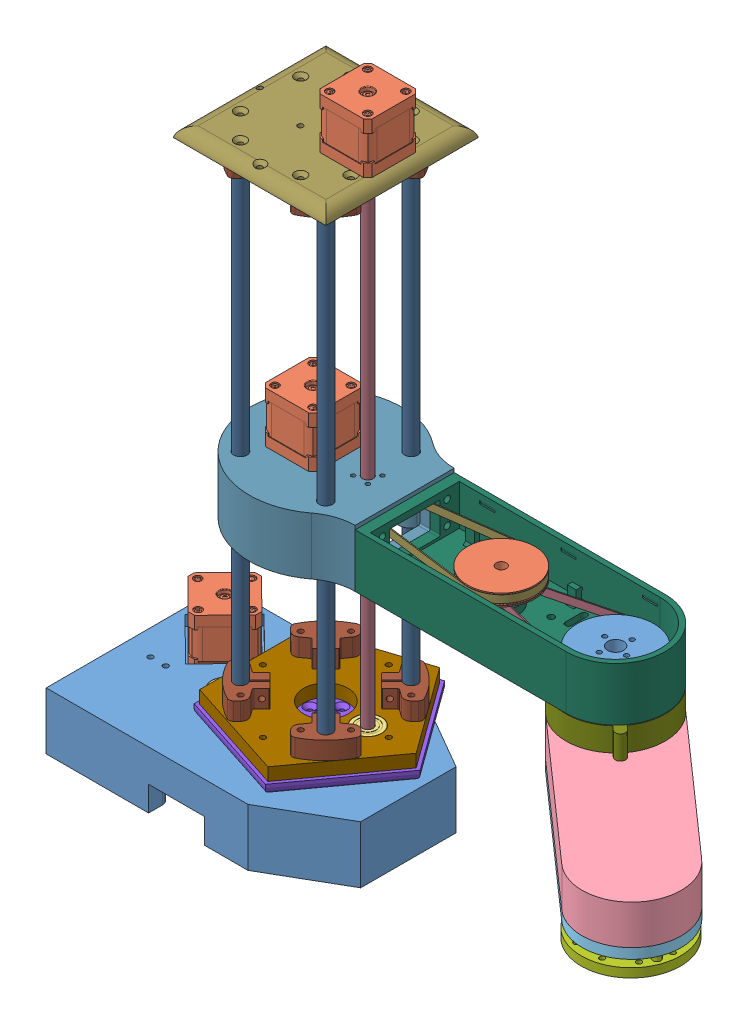
SolidWorks assembly SCARA ENSAMBLE, configuration SCARA Robot. Lengths in mm.
Overall size (541.01 508 220.87).
62 component instances, 33 part files, 149 mates.
Components (placement in the parent):
- 0-Base-1: 0-Base [Base] at origin size (215 45 140)
- Stepper NEMA 17 -  20mm shaft-1: Stepper NEMA 17 -  20mm shaft [Stepper NEMA 17 -  20mm shaft] at (-89.369 63.0261 0.1561) x (-0.712104 0 -0.702074) z (0 -1 0) size (41 41 60)
- Ball Bearing 608 - 8x22x7mm-2: Ball Bearing 608 - 8x22x7mm [Ball Bearing 608 - 8x22x7mm] at (-36.5 3 0) x (0.982643 0 -0.185507) z (0.185507 0 0.982643) size (22 7 22)
- Ball Bearing 608 - 8x22x7mm-3: Ball Bearing 608 - 8x22x7mm [Ball Bearing 608 - 8x22x7mm] at (-36.5 -7.5 0) x (0.997797 0 -0.066338) z (0.066338 0 0.997797) size (22 7 22)
- Thrust Bearing - 40x60x13-3: Thrust Bearing - 40x60x13 [Thrust Bearing - 40x60x13] at (42.5 -13 0) size (60 13 60)
- Thrust Bearing - 40x60x13-4: Thrust Bearing - 40x60x13 [Thrust Bearing - 40x60x13] at (42.5 10 0) x (0.998314 0 0.058039) z (-0.058039 0 0.998314) size (60 13 60)
- 02-ENGRANEGT2J1BASE110-2: 02-ENGRANEGT2J1BASE110 [GT2 Pulley - Parametric] at (42.5 -11.2 0) x (-1 0 0) z (0 0 1) size (71.92 22.4 71.92)
- 01-ENGRANEGT2J122-80-2: 01-ENGRANEGT2J122-80 [GT2 Pulley - Parametric] at (-36.5 -26.3 0) x (0.998061 0 0.062248) z (-0.062248 0 0.998061) size (52.82 18.8 52.82)
- GT2 Pulley - Parametric-1: GT2 Pulley - Parametric [GT2 Pulley - Parametric] at (-69.2568 -19.3 -32.2954) x (-0.837169 0 -0.546944) z (-0.546944 0 0.837169) size (14.62 15.2 14.62)
- 1-J1 ACOPLEMOD-1: 1-J1 ACOPLEMOD [J1 coupler] at (42.5 23 0) x (0 0 1) z (-1 0 0) size (141.07 27 134.16)
- 2-TapaZ-2: 2-TapaZ [Z-axis Bottom Plate] at (42.5 31 0) x (0 0 -1) z (1 0 0) size (135.19 10 128.57)
- Smooth Rod D10mm L400mm-1: Smooth Rod D10mm L400mm [Smooth Rod D10mm L400mm] at (76.0876 25 -33.5876) x (-0.2209 0 0.975296) z (-0.975296 0 -0.2209) size (10 400 10)
- Smooth Rod D10mm L400mm-2: Smooth Rod D10mm L400mm [Smooth Rod D10mm L400mm] at (76.0876 25 33.5876) size (10 400 10)
- Smooth Rod D10mm L400mm-3: Smooth Rod D10mm L400mm [Smooth Rod D10mm L400mm] at (8.9124 25 33.5876) size (10 400 10)
- Smooth Rod D10mm L400mm-4: Smooth Rod D10mm L400mm [Smooth Rod D10mm L400mm] at (8.9124 25 -33.5876) size (10 400 10)
- 11-SOPORTEVARILLA-1: 11-SOPORTEVARILLA [Smooth Rod Clamp] at (76.0876 41 33.5876) x (0.707107 0 -0.707107) z (0.707107 0 0.707107) size (39.1 14 26.4)
- 11-SOPORTEVARILLA-2: 11-SOPORTEVARILLA [Smooth Rod Clamp] at (8.9124 41 33.5876) x (0.707107 0 0.707107) z (-0.707107 0 0.707107) size (39.1 14 26.4)
- 11-SOPORTEVARILLA-3: 11-SOPORTEVARILLA [Smooth Rod Clamp] at (8.9124 41 -33.5876) x (-0.707107 0 0.707107) z (-0.707107 0 -0.707107) size (39.1 14 26.4)
- 11-SOPORTEVARILLA-4: 11-SOPORTEVARILLA [Smooth Rod Clamp] at (76.0876 41 -33.5876) x (-0.707107 0 -0.707107) z (0.707107 0 -0.707107) size (39.1 14 26.4)
- 10-TOPZ-1: 10-TOPZ [Z-axis Top Plate] at (42.5 425 0) x (0 0 -1) z (1 0 0) size (120 26 120)
- 11-SOPORTEVARILLA-5: 11-SOPORTEVARILLA [Smooth Rod Clamp] at (8.9124 411 33.5876) x (0.707107 0 0.707107) z (-0.707107 0 0.707107) size (39.1 14 26.4)
- 11-SOPORTEVARILLA-6: 11-SOPORTEVARILLA [Smooth Rod Clamp] at (76.0876 411 33.5876) x (0.707107 0 -0.707107) z (0.707107 0 0.707107) size (39.1 14 26.4)
- 11-SOPORTEVARILLA-7: 11-SOPORTEVARILLA [Smooth Rod Clamp] at (76.0876 411 -33.5876) x (-0.707107 0 -0.707107) z (0.707107 0 -0.707107) size (39.1 14 26.4)
- 11-SOPORTEVARILLA-8: 11-SOPORTEVARILLA [Smooth Rod Clamp] at (8.9124 411 -33.5876) x (-0.707107 0 0.707107) z (-0.707107 0 -0.707107) size (39.1 14 26.4)
- Lead Screw D8mm L380mm-1: Lead Screw D8mm L380mm [Lead Screw D8mm L380mm] at (75.5 33 0) x (0.999653 0 0.026358) z (-0.026358 0 0.999653) size (8 380 8)
- Ball Bearing 608 - 8x22x7mm-4: Ball Bearing 608 - 8x22x7mm [Ball Bearing 608 - 8x22x7mm] at (75.5 34 0) x (0.948058 0 -0.318097) z (0.318097 0 0.948058) size (22 7 22)
- Stepper NEMA 17 -  20mm shaft-2: Stepper NEMA 17 -  20mm shaft [Stepper NEMA 17 -  20mm shaft] at (38.2709 494.0261 8.4614) x (0 0 -1) z (0 -1 0) size (41 41 60)
- 3-J1CENTRAL-1: 3-J1CENTRAL [Z-axis Mount Platform] at (42.5 211.1984 0) x (0 0 1) z (1 0 0) size (120 45 122)
- 4-J1CENTRALBRAZO-1: 4-J1CENTRALBRAZO [Arm 1] at (270.5 166.1984 0) size (205 42 78)
- Ball Bearing 608 - 8x22x7mm-5: Ball Bearing 608 - 8x22x7mm [Ball Bearing 608 - 8x22x7mm] at (180.5 182.1984 0) x (0.62791 0 0.778286) z (0.778286 0 -0.62791) size (22 7 22)
- Ball Bearing 608 - 8x22x7mm-6: Ball Bearing 608 - 8x22x7mm [Ball Bearing 608 - 8x22x7mm] at (180.5 173.1984 0) x (0.619443 0 0.785042) z (0.785042 0 -0.619443) size (22 7 22)
- 5-COPLEJ1J2-1: 5-COPLEJ1J2 [J2 Coupler] at (270.5 147.1984 0) x (0.198234 0 -0.980155) z (0.980155 0 0.198234) size (78 24 80.24)
- Thrust Bearing 35x52x12mm-1: Thrust Bearing 35x52x12mm [Thrust Bearing 35x52x12mm] at (270.5 154.1984 0) x (1 0 0.000333) z (-0.000333 0 1) size (52 12 52)
- Ball Bearing 30x42x7mm-1: Ball Bearing 30x42x7mm [Ball Bearing 30x42x7mm] at (270.5 169.1984 0) x (1 0 0.000333) z (-0.000333 0 1) size (42 7 42)
- GT2 Pulley - 92 teeth - J2-1: GT2 Pulley - 92 teeth - J2 [GT2 Pulley - Parametric] at (270.5 184.3984 0) x (0.980155 0 0.198234) z (-0.198234 0 0.980155) size (60.46 20.4 60.46)
- GT2 Pulley - 23 - 80 teeth-1: GT2 Pulley - 23 - 80 teeth [GT2 Pulley - Parametric] at (180.5 200.9984 0) x (-0.873164 0 -0.487427) z (-0.487427 0 0.873164) size (52.82 18.8 52.82)
- Thrust Bearing 35x52x12mm-2: Thrust Bearing 35x52x12mm [Thrust Bearing 35x52x12mm] at (270.5 176.1984 0) x (1 0 0.000333) z (-0.000333 0 1) size (52 12 52)
- Stepper NEMA 17 -  20mm shaft-3: Stepper NEMA 17 -  20mm shaft [Stepper NEMA 17 -  20mm shaft] at (-4.7291 272.2245 8.4614) x (0 0 -1) z (0 -1 0) size (41 41 60)
- GT2 Pulley - Parametric-2: GT2 Pulley - Parametric [GT2 Pulley - Parametric] at (32.5 200.9984 0) x (-0.529245 0 -0.848469) z (-0.848469 0 0.529245) size (14.62 15.2 14.62)
- Linear Bearing 10x19x29mm-1: Linear Bearing 10x19x29mm [Linear Bearing 10x19x29mm] at (8.9124 176.1984 -33.5876) x (0.996362 0 -0.085221) z (0.085221 0 0.996362) size (19 29 19)
- Linear Bearing 10x19x29mm-2: Linear Bearing 10x19x29mm [Linear Bearing 10x19x29mm] at (76.0876 176.1984 -33.5876) x (0.940518 0 0.339744) z (-0.339744 0 0.940518) size (19 29 19)
- Linear Bearing 10x19x29mm-3: Linear Bearing 10x19x29mm [Linear Bearing 10x19x29mm] at (8.9124 176.1984 33.5876) size (19 29 19)
- Linear Bearing 10x19x29mm-6: Linear Bearing 10x19x29mm [Linear Bearing 10x19x29mm] at (76.0876 176.1984 33.5876) size (19 29 19)
- 6-J2BRZO-1: 6-J2BRZO [Arm 2] at (378.46 147.1984 95.2924) x (0.749722 0 0.661753) z (0.661753 0 -0.749722) size (222 31 78)
- 7-J2TAPABRZO-1: 7-J2TAPABRZO [Arm 2 Cover] at (378.46 108.1984 95.2924) x (0.749722 0 0.661753) z (-0.661753 0 0.749722) size (222 8 78)
- Micro switch-1: Micro switch [Micro switch] at (217.6469 166.1984 9.5547) x (0.882948 0 -0.469472) z (0 -1 0) size (21.91 25.05 6)
- 8-J3COPLE-1: 8-J3COPLE [J3 Coupler] at (372.8371 90.1984 90.3293) x (-0.943757 0 -0.330639) z (0.330639 0 -0.943757) size (77.59 22 78)
- Ball Bearing 30x42x7mm-2: Ball Bearing 30x42x7mm [Ball Bearing 30x42x7mm] at (372.8371 116.1984 90.3293) x (-0.837351 0 -0.546665) z (-0.546665 0 0.837351) size (42 7 42)
- Thrust Bearing 35x52x12mm-3: Thrust Bearing 35x52x12mm [Thrust Bearing 35x52x12mm] at (372.8371 116.1984 90.3293) x (0.88853 0 -0.458819) z (0.458819 0 0.88853) size (52 12 52)
- Thrust Bearing 35x52x12mm-4: Thrust Bearing 35x52x12mm [Thrust Bearing 35x52x12mm] at (372.8371 108.1984 90.3293) x (-0.531744 0 -0.846905) z (-0.846905 0 0.531744) size (52 12 52)
- GT2 Pulley - 90 teeth - J3-1: GT2 Pulley - 90 teeth - J3 [GT2 Pulley - Parametric] at (372.8371 126.3984 90.3293) x (-0.330639 0 0.943757) z (-0.943757 0 -0.330639) size (59.19 21.4 59.19)
- GT2 Pulley - Parametric-3: GT2 Pulley - Parametric [GT2 Pulley - Parametric] at (266.0017 126.3984 -3.9705) x (0.907133 0 -0.420845) z (0.420845 0 0.907133) size (14.62 15.2 14.62)
- Micro switch-3: Micro switch [Micro switch] at (-8.7411 16 2.5547) x (0.882948 0 -0.469472) z (0 -1 0) size (21.91 25.05 6)
- Micro switch-4: Micro switch [Micro switch] at (333.7206 108.1984 68.5469) x (0.972639 0 0.23232) z (0 -1 0) size (21.91 25.05 6)
- Lead Screw Nut 8mm-1: Lead Screw Nut 8mm [Lead Screw Nut 8mm] at (75.5 201.6984 0) size (22 15 22)
- Micro switch-5: Micro switch [Micro switch] at (14.25 412 6) x (1 0 0) z (0 0 -1) size (21.91 25.05 6)
- GT2 Belt 200mm-1: GT2 Belt 200mm [GT2 Belt 400mm] at (-36.5 -25.3 0) x (0.712104 0 0.702074) z (-0.702074 0 0.712104) size (79.45 6 52.6)
- GT2 Belt 300mm 2-1: GT2 Belt 300mm 2 [GT2 Belt 400mm] at (42.5 -17.2 0) size (122.6 6 71.6)
- GT2 Belt 400mm-1: GT2 Belt 400mm [GT2 Belt 400mm] at (180.5 194.9984 0) size (181.45 6 52.6)
- GT2 Belt 300mm-1: GT2 Belt 300mm [GT2 Belt 400mm] at (270.5 185.3984 0) size (128.2 6 60.2)
- GT2 Belt 400mm 2-1: GT2 Belt 400mm 2 [GT2 Belt 400mm] at (372.8371 126.3984 90.3293) x (0.749722 0 0.661753) z (-0.661753 0 0.749722) size (179.1 6 58.9)
- Ball Bearing 35x47x7mm-1: Ball Bearing 35x47x7mm [Ball Bearing 30x42x7mm] at (42.5 0 0) x (0.999968 0 0.008039) z (-0.008039 0 0.999968) size (47 7 47)
Mates (geometry in assembly coordinates):
- Concentric1: concentric aligned: cylinder of Base-1 through (-69.2568 0 -32.2954) axis (0 1 0) radius 12.5; cylinder of Stepper NEMA 17 -  20mm shaft-1 through (-69.2568 0.01 -32.2954) axis (0 1 0) radius 11.5
- Parallel1: parallel anti-aligned: plane of Base-1 through (-69.0361 2 -1.1835) normal (0.702074 0 -0.712104); plane of Stepper NEMA 17 -  20mm shaft-1 through (-71.5435 2 -5.762) normal (-0.702074 0 0.712104)
- Coincident2: coincident anti-aligned: plane of Base-1 through (0 2 0) normal (0 1 0); plane of Stepper NEMA 17 -  20mm shaft-1 through (-83.6493 2 -17.6973) normal (0 -1 0)
- Concentric2: concentric anti-aligned: cylinder of Base-1 through (-36.5 3 0) axis (0 1 0) radius 11; cylinder of Ball Bearing 608 - 8x22x7mm-2 through (-36.5 10 0) axis (0 -1 0) radius 11
- Coincident3: coincident anti-aligned: plane of Base-1 through (-36.5 3 0) normal (0 1 0); plane of Ball Bearing 608 - 8x22x7mm-2 through (-36.5 3 0) normal (0 -1 0)
- Concentric3: concentric anti-aligned: cylinder of Base-1 through (-36.5 -8.5 0) axis (0 1 0) radius 11; cylinder of Ball Bearing 608 - 8x22x7mm-3 through (-36.5 -0.5 0) axis (0 -1 0) radius 11
- Concentric4: concentric aligned: cylinder of Base-1 through (42.5 0 0) axis (0 1 0) radius 20; cylinder of Thrust Bearing - 40x60x13-4 through (42.5 19.2 0) axis (0 1 0) radius 30
- Coincident5: coincident anti-aligned: plane of Base-1 through (0 10 0) normal (0 1 0); plane of Thrust Bearing - 40x60x13-4 through (42.5 10 0) normal (0 -1 0)
- Concentric5: concentric anti-aligned: cylinder of Base-1 through (42.5 -8 0) axis (0 1 0) radius 30.5; cylinder of Thrust Bearing - 40x60x13-3 through (42.5 -9.2 0) axis (0 -1 0) radius 30
- Coincident6: coincident anti-aligned: plane of Base-1 through (0 0 0) normal (0 -1 0); plane of Thrust Bearing - 40x60x13-3 through (42.5 0 0) normal (0 1 0)
- Concentric6: concentric anti-aligned: cylinder of Ball Bearing 608 - 8x22x7mm-3 through (-36.5 -0.5 0) axis (0 -1 0) radius 4; cylinder of GT2 Pulley - 22 - 80 teeth-2 through (-36.5 -27.5 0) axis (0 1 0) radius 4
- Concentric8: concentric anti-aligned: cylinder of Thrust Bearing - 40x60x13-3 through (42.5 -3.8 0) axis (0 1 0) radius 20; cylinder of GT2 Pulley - 110 teeth - J1-2 through (42.5 3 0) axis (0 -1 0) radius 17.5
- Coincident9: coincident anti-aligned: plane of Thrust Bearing - 40x60x13-3 through (42.5 -13 0) normal (0 -1 0); plane of GT2 Pulley - 110 teeth - J1-2 through (42.5 -13 0) normal (0 1 0)
- Concentric9: concentric anti-aligned: cylinder of Stepper NEMA 17 -  20mm shaft-1 through (-69.2568 -20 -32.2954) axis (0 1 0) radius 2.5; cylinder of GT2 Pulley - Parametric-1 through (-69.2568 -12.3 -32.2954) axis (0 -1 0) radius 3
- Coincident10: coincident aligned: plane of GT2 Pulley - 22 - 80 teeth-2 through (-36.5 -19.3 0) normal (0 -1 0); plane of GT2 Pulley - Parametric-1 through (-69.2568 -19.3 -32.2954) normal (0 -1 0)
- Coincident11: coincident anti-aligned: plane of Thrust Bearing - 40x60x13-4 through (42.5 23 0) normal (0 1 0); plane of J1 coupler-1 through (42.5 23 0) normal (0 -1 0)
- Concentric10: concentric: cylinder of Thrust Bearing - 40x60x13-4 through (42.5 18.2 0) axis (0 -1 0) radius 30; cylinder of J1 coupler-1 through (42.5 31 0) axis (0 -1 0) radius 60
- Concentric11: concentric anti-aligned: cylinder of GT2 Pulley - 110 teeth - J1-2 through (55 3 0) axis (0 -1 0) radius 1.8; cylinder of J1 coupler-1 through (55 31 0) axis (0 1 0) radius 1.8
- Coincident13: coincident anti-aligned: plane of Base-1 through (-36.5 -0.5 0) normal (0 -1 0); plane of Ball Bearing 608 - 8x22x7mm-3 through (-36.5 -0.5 0) normal (0 1 0)
- Concentric12: concentric anti-aligned: cylinder of J1 coupler-1 through (76.0876 23 -33.5876) axis (0 1 0) radius 3.875; cylinder of Smooth Rod D10mm L400mm-1 through (76.0876 425 -33.5876) axis (0 -1 0) radius 5
- Coincident14: coincident: plane of J1 coupler-1 through (76.0876 25 -33.5876) normal (0 1 0); plane of Smooth Rod D10mm L400mm-1 through (76.0876 25 -33.5876) normal (0 -1 0)
- Concentric13: concentric anti-aligned: cylinder of J1 coupler-1 through (8.9124 23 -33.5876) axis (0 1 0) radius 3.875; cylinder of Smooth Rod D10mm L400mm-4 through (8.9124 425 -33.5876) axis (0 -1 0) radius 5
- Concentric14: concentric anti-aligned: cylinder of J1 coupler-1 through (8.9124 23 33.5876) axis (0 1 0) radius 3.875; cylinder of Smooth Rod D10mm L400mm-3 through (8.9124 425 33.5876) axis (0 -1 0) radius 5
- Concentric15: concentric anti-aligned: cylinder of J1 coupler-1 through (76.0876 23 33.5876) axis (0 1 0) radius 3.875; cylinder of Smooth Rod D10mm L400mm-2 through (76.0876 425 33.5876) axis (0 -1 0) radius 5
- Coincident15: coincident aligned: plane of Smooth Rod D10mm L400mm-1 through (76.0876 425 -33.5876) normal (0 1 0); plane of Smooth Rod D10mm L400mm-2 through (76.0876 425 33.5876) normal (0 1 0)
- Coincident16: coincident aligned: plane of Smooth Rod D10mm L400mm-1 through (76.0876 425 -33.5876) normal (0 1 0); plane of Smooth Rod D10mm L400mm-3 through (8.9124 425 33.5876) normal (0 1 0)
- Coincident17: coincident aligned: plane of Smooth Rod D10mm L400mm-1 through (76.0876 425 -33.5876) normal (0 1 0); plane of Smooth Rod D10mm L400mm-4 through (8.9124 425 -33.5876) normal (0 1 0)
- Concentric16: concentric: cylinder of J1 coupler-1 through (42.5 31 0) axis (0 -1 0) radius 60; cylinder of Z-axis Bottom Plate-2 through (42.5 41 0) axis (0 -1 0) radius 60
- Concentric17: concentric anti-aligned: cylinder of Z-axis Bottom Plate-2 through (76.0876 31 -33.5876) axis (0 1 0) radius 4.975; cylinder of Smooth Rod D10mm L400mm-1 through (76.0876 425 -33.5876) axis (0 -1 0) radius 5
- Coincident18: coincident anti-aligned: plane of J1 coupler-1 through (42.5 31 0) normal (0 1 0); plane of Z-axis Bottom Plate-2 through (42.5 31 0) normal (0 -1 0)
- Concentric18: concentric aligned: cylinder of Smooth Rod D10mm L400mm-2 through (76.0876 425 33.5876) axis (0 -1 0) radius 5; cylinder of Smooth Rod Clamp-1 through (76.0876 55 33.5876) axis (0 -1 0) radius 4
- Concentric19: concentric anti-aligned: cylinder of Z-axis Bottom Plate-2 through (66.1881 31 43.4871) axis (0 1 0) radius 2.05; cylinder of Smooth Rod Clamp-1 through (66.1881 55 43.4871) axis (0 -1 0) radius 2.05
- Coincident19: coincident anti-aligned: plane of Z-axis Bottom Plate-2 through (42.5 41 0) normal (0 1 0); plane of Smooth Rod Clamp-1 through (66.1881 41 43.4871) normal (0 -1 0)
- Coincident20: coincident anti-aligned: plane of Z-axis Bottom Plate-2 through (42.5 41 0) normal (0 1 0); plane of Smooth Rod Clamp-4 through (85.9871 41 -23.6881) normal (0 -1 0)
- Concentric20: concentric aligned: cylinder of Smooth Rod D10mm L400mm-1 through (76.0876 425 -33.5876) axis (0 -1 0) radius 5; cylinder of Smooth Rod Clamp-4 through (76.0876 55 -33.5876) axis (0 -1 0) radius 4
- Concentric21: concentric anti-aligned: cylinder of Z-axis Bottom Plate-2 through (66.1881 31 -43.4871) axis (0 1 0) radius 2.05; cylinder of Smooth Rod Clamp-4 through (66.1881 55 -43.4871) axis (0 -1 0) radius 2.05
- Coincident21: coincident anti-aligned: plane of Z-axis Bottom Plate-2 through (42.5 41 0) normal (0 1 0); plane of Smooth Rod Clamp-2 through (-0.9871 41 23.6881) normal (0 -1 0)
- Concentric22: concentric aligned: cylinder of Smooth Rod D10mm L400mm-3 through (8.9124 425 33.5876) axis (0 -1 0) radius 5; cylinder of Smooth Rod Clamp-2 through (8.9124 55 33.5876) axis (0 -1 0) radius 4
- Concentric23: concentric anti-aligned: cylinder of Z-axis Bottom Plate-2 through (18.8119 31 43.4871) axis (0 1 0) radius 2.05; cylinder of Smooth Rod Clamp-2 through (18.8119 55 43.4871) axis (0 -1 0) radius 2.05
- Concentric24: concentric aligned: cylinder of Smooth Rod D10mm L400mm-4 through (8.9124 425 -33.5876) axis (0 -1 0) radius 5; cylinder of Smooth Rod Clamp-3 through (8.9124 55 -33.5876) axis (0 -1 0) radius 4
- Concentric25: concentric anti-aligned: cylinder of Z-axis Bottom Plate-2 through (-0.9871 31 -23.6881) axis (0 1 0) radius 2.05; cylinder of Smooth Rod Clamp-3 through (-0.9871 55 -23.6881) axis (0 -1 0) radius 2.05
- Coincident22: coincident anti-aligned: plane of Z-axis Bottom Plate-2 through (42.5 41 0) normal (0 1 0); plane of Smooth Rod Clamp-3 through (18.8119 41 -43.4871) normal (0 -1 0)
- Coincident23: coincident anti-aligned: plane of Z-axis Top Plate-1 through (42.5 425 0) normal (0 -1 0); plane of Smooth Rod Clamp-6 through (66.1881 425 43.4871) normal (0 1 0)
- Concentric26: concentric anti-aligned: cylinder of Z-axis Top Plate-1 through (85.9871 425 23.6881) axis (0 1 0) radius 2.05; cylinder of Smooth Rod Clamp-6 through (85.9871 425 23.6881) axis (0 -1 0) radius 2.05
- Concentric27: concentric anti-aligned: cylinder of Z-axis Top Plate-1 through (66.1881 425 43.4871) axis (0 1 0) radius 2.05; cylinder of Smooth Rod Clamp-6 through (66.1881 425 43.4871) axis (0 -1 0) radius 2.05
- Coincident24: coincident anti-aligned: plane of Z-axis Top Plate-1 through (42.5 425 0) normal (0 -1 0); plane of Smooth Rod Clamp-8 through (18.8119 425 -43.4871) normal (0 1 0)
- Concentric28: concentric anti-aligned: cylinder of Z-axis Top Plate-1 through (18.8119 425 -43.4871) axis (0 1 0) radius 2.05; cylinder of Smooth Rod Clamp-8 through (18.8119 425 -43.4871) axis (0 -1 0) radius 2.05
- Concentric29: concentric anti-aligned: cylinder of Z-axis Top Plate-1 through (-0.9871 425 -23.6881) axis (0 1 0) radius 2.05; cylinder of Smooth Rod Clamp-8 through (-0.9871 425 -23.6881) axis (0 -1 0) radius 2.05
- Coincident25: coincident anti-aligned: plane of Z-axis Top Plate-1 through (42.5 425 0) normal (0 -1 0); plane of Smooth Rod Clamp-7 through (85.9871 425 -23.6881) normal (0 1 0)
- Concentric32: concentric anti-aligned: cylinder of Z-axis Top Plate-1 through (66.1881 425 -43.4871) axis (0 1 0) radius 2.05; cylinder of Smooth Rod Clamp-7 through (66.1881 425 -43.4871) axis (0 -1 0) radius 2.05
- Concentric33: concentric anti-aligned: cylinder of Z-axis Top Plate-1 through (85.9871 425 -23.6881) axis (0 1 0) radius 2.05; cylinder of Smooth Rod Clamp-7 through (85.9871 425 -23.6881) axis (0 -1 0) radius 2.05
- Coincident26: coincident anti-aligned: plane of Z-axis Top Plate-1 through (42.5 425 0) normal (0 -1 0); plane of Smooth Rod Clamp-5 through (-0.9871 425 23.6881) normal (0 1 0)
- Concentric34: concentric anti-aligned: cylinder of Z-axis Top Plate-1 through (-0.9871 425 23.6881) axis (0 1 0) radius 2.05; cylinder of Smooth Rod Clamp-5 through (-0.9871 425 23.6881) axis (0 -1 0) radius 2.05
- Concentric35: concentric anti-aligned: cylinder of Z-axis Top Plate-1 through (18.8119 425 43.4871) axis (0 1 0) radius 2.05; cylinder of Smooth Rod Clamp-5 through (18.8119 425 43.4871) axis (0 -1 0) radius 2.05
- Concentric36: concentric aligned: cylinder of Z-axis Bottom Plate-2 through (75.5 34 0) axis (0 1 0) radius 11; cylinder of Z-axis Top Plate-1 through (75.5 425 0) axis (0 1 0) radius 12.5
- Concentric37: concentric aligned: cylinder of Smooth Rod D10mm L400mm-2 through (76.0876 425 33.5876) axis (0 -1 0) radius 5; cylinder of Smooth Rod Clamp-6 through (76.0876 425 33.5876) axis (0 -1 0) radius 4
- Coincident27: coincident anti-aligned: plane of Smooth Rod D10mm L400mm-2 through (76.0876 425 33.5876) normal (0 1 0); plane of Z-axis Top Plate-1 through (42.5 425 0) normal (0 -1 0)
- Concentric38: concentric anti-aligned: cylinder of Z-axis Bottom Plate-2 through (75.5 34 0) axis (0 1 0) radius 11; cylinder of Ball Bearing 608 - 8x22x7mm-4 through (75.5 41 0) axis (0 -1 0) radius 11
- Coincident28: coincident anti-aligned: plane of Z-axis Bottom Plate-2 through (75.5 34 0) normal (0 1 0); plane of Ball Bearing 608 - 8x22x7mm-4 through (75.5 34 0) normal (0 -1 0)
- Concentric39: concentric aligned: cylinder of Lead Screw D8mm L380mm-1 through (75.5 413 0) axis (0 -1 0) radius 4; cylinder of Ball Bearing 608 - 8x22x7mm-4 through (75.5 41 0) axis (0 -1 0) radius 4
- Concentric40: concentric aligned: cylinder of Z-axis Top Plate-1 through (75.5 425 0) axis (0 1 0) radius 12.5; cylinder of Stepper NEMA 17 -  20mm shaft-2 through (75.5 411 0) axis (0 1 0) radius 2.5
- Coincident29: coincident anti-aligned: plane of Z-axis Top Plate-1 through (42.5 433 0) normal (0 1 0); plane of Stepper NEMA 17 -  20mm shaft-2 through (55 433 0) normal (0 -1 0)
- Concentric41: concentric anti-aligned: cylinder of Z-axis Top Plate-1 through (91 425 15.5) axis (0 1 0) radius 1.6; cylinder of Stepper NEMA 17 -  20mm shaft-2 through (91 437 15.5) axis (0 -1 0) radius 1.5
- Coincident30: coincident anti-aligned: plane of Lead Screw D8mm L380mm-1 through (75.5 413 0) normal (0 1 0); plane of Stepper NEMA 17 -  20mm shaft-2 through (75.5 413 0) normal (0 -1 0)
- Concentric42: concentric anti-aligned: cylinder of Smooth Rod D10mm L400mm-1 through (76.0876 425 -33.5876) axis (0 -1 0) radius 5; cylinder of Z-axis Mount Platform-1 through (76.0876 166.1984 -33.5876) axis (0 1 0) radius 7.5
- Concentric43: concentric aligned: cylinder of Smooth Rod D10mm L400mm-2 through (76.0876 425 33.5876) axis (0 -1 0) radius 5; cylinder of Z-axis Mount Platform-1 through (76.0876 211.1984 33.5876) axis (0 -1 0) radius 5.25
- Concentric44: concentric anti-aligned: cylinder of Z-axis Mount Platform-1 through (-17.501 182.6984 -25.5) axis (1 0 0) radius 2.55; cylinder of Arm 1-1 through (309.501 182.6984 -25.5) axis (-1 0 0) radius 2.55
- Coincident31: coincident anti-aligned: plane of Z-axis Mount Platform-1 through (104.5 166.1984 0) normal (1 0 0); plane of Arm 1-1 through (104.5 176.1984 -39) normal (-1 0 0)
- Concentric451: concentric aligned: cylinder of Arm 1-1 through (180.5 182.1984 0) axis (0 -1 0) radius 11; cylinder of Ball Bearing 608 - 8x22x7mm-5 through (180.5 175.3984 0) axis (0 -1 0) radius 8.25
- Coincident321: coincident anti-aligned: plane of Arm 1-1 through (180.5 175.1984 0) normal (0 1 0); plane of Ball Bearing 608 - 8x22x7mm-5 through (180.5 175.1984 0) normal (0 -1 0)
- Coincident33: coincident anti-aligned: plane of Arm 1-1 through (180.5 173.1984 0) normal (0 -1 0); plane of Ball Bearing 608 - 8x22x7mm-6 through (180.5 173.1984 0) normal (0 1 0)
- Concentric46: concentric anti-aligned: cylinder of Arm 1-1 through (180.5 173.1984 0) axis (0 -1 0) radius 11; cylinder of Ball Bearing 608 - 8x22x7mm-6 through (180.5 166.1984 0) axis (0 1 0) radius 11
- Coincident34: coincident anti-aligned: plane of J2 Coupler-1 through (270.5 154.1984 0) normal (0 1 0); plane of Thrust Bearing 35x52x12mm-1 through (270.5 154.1984 0) normal (0 -1 0)
- Concentric47: concentric anti-aligned: cylinder of J2 Coupler-1 through (270.5 154.1984 0) axis (0 1 0) radius 26.5; cylinder of Thrust Bearing 35x52x12mm-1 through (270.5 166.1984 0) axis (0 -1 0) radius 26
- Concentric48: concentric anti-aligned: cylinder of Arm 1-1 through (270.5 169.1984 0) axis (0 1 0) radius 21; cylinder of Ball Bearing 30x42x7mm-1 through (270.5 176.1984 0) axis (0 -1 0) radius 21
- Coincident35: coincident anti-aligned: plane of Arm 1-1 through (270.5 169.1984 0) normal (0 1 0); plane of Ball Bearing 30x42x7mm-1 through (270.5 169.1984 0) normal (0 -1 0)
- Concentric49: concentric anti-aligned: cylinder of Arm 1-1 through (270.5 166.1984 0) axis (0 1 0) radius 17.5; cylinder of J2 Coupler-1 through (270.5 171.1984 0) axis (0 -1 0) radius 15
- Coincident36: coincident anti-aligned: plane of Arm 1-1 through (270.5 166.1984 0) normal (0 -1 0); plane of Thrust Bearing 35x52x12mm-1 through (270.5 166.1984 0) normal (0 1 0)
- Concentric50: concentric anti-aligned: cylinder of Ball Bearing 608 - 8x22x7mm-5 through (180.5 175.1984 0) axis (0 1 0) radius 4; cylinder of GT2 Pulley - 23 - 80 teeth-1 through (180.5 202.1984 0) axis (0 -1 0) radius 4
- Concentric51: concentric aligned: cylinder of J2 Coupler-1 through (270.5 147.1984 0) axis (0 1 0) radius 6.25; cylinder of GT2 Pulley - 92 teeth - J2-1 through (270.5 172.1984 0) axis (0 1 0) radius 6.25
- Coincident38: coincident anti-aligned: plane of GT2 Pulley - 92 teeth - J2-1 through (270.5 188.1984 0) normal (0 -1 0); plane of Thrust Bearing 35x52x12mm-2 through (270.5 188.1984 0) normal (0 1 0)
- Concentric52: concentric anti-aligned: cylinder of GT2 Pulley - 92 teeth - J2-1 through (270.5 172.1984 0) axis (0 1 0) radius 15; cylinder of Thrust Bearing 35x52x12mm-2 through (270.5 179.9984 0) axis (0 -1 0) radius 17.5
- Coincident39: coincident anti-aligned: plane of Arm 1-1 through (270.5 176.1984 0) normal (0 1 0); plane of Thrust Bearing 35x52x12mm-2 through (270.5 176.1984 0) normal (0 -1 0)
- Concentric53: concentric anti-aligned: cylinder of Z-axis Mount Platform-1 through (-17.501 200.6984 -25.5) axis (1 0 0) radius 2.55; cylinder of Arm 1-1 through (309.501 200.6984 -25.5) axis (-1 0 0) radius 2.55
- Concentric54: concentric aligned: cylinder of Z-axis Mount Platform-1 through (32.5 166.1984 0) axis (0 1 0) radius 12.5; cylinder of Stepper NEMA 17 -  20mm shaft-3 through (32.5 189.1984 0) axis (0 1 0) radius 2.5
- Concentric55: concentric anti-aligned: cylinder of Z-axis Mount Platform-1 through (17 166.1984 15.5) axis (0 1 0) radius 1.6; cylinder of Stepper NEMA 17 -  20mm shaft-3 through (17 215.1984 15.5) axis (0 -1 0) radius 1.5
- Coincident40: coincident anti-aligned: plane of Z-axis Mount Platform-1 through (42.5 211.1984 0) normal (0 1 0); plane of Stepper NEMA 17 -  20mm shaft-3 through (12 211.1984 0) normal (0 -1 0)
- Concentric56: concentric anti-aligned: cylinder of Stepper NEMA 17 -  20mm shaft-3 through (32.5 189.1984 0) axis (0 1 0) radius 2.5; cylinder of GT2 Pulley - Parametric-2 through (32.5 207.9984 0) axis (0 -1 0) radius 7.3122
- Coincident41: coincident aligned: plane of GT2 Pulley - 23 - 80 teeth-1 through (180.5 193.9984 0) normal (0 1 0); plane of GT2 Pulley - Parametric-2 through (32.5 193.9984 0) normal (0 1 0)
- Concentric58: concentric anti-aligned: cylinder of Z-axis Mount Platform-1 through (8.9124 166.1984 33.5876) axis (0 1 0) radius 7.5; cylinder of Linear Bearing 10x19x29mm-3 through (8.9124 205.1984 33.5876) axis (0 -1 0) radius 9.5
- Coincident44: coincident anti-aligned: plane of Z-axis Mount Platform-1 through (104.4919 205.1984 81) normal (0 -1 0); plane of Linear Bearing 10x19x29mm-3 through (8.9124 205.1984 33.5876) normal (0 1 0)
- Coincident45: coincident anti-aligned: plane of Z-axis Mount Platform-1 through (104.4919 205.1984 81) normal (0 -1 0); plane of Linear Bearing 10x19x29mm-6 through (76.0876 205.1984 33.5876) normal (0 1 0)
- Concentric59: concentric anti-aligned: cylinder of Z-axis Mount Platform-1 through (76.0876 166.1984 33.5876) axis (0 1 0) radius 7.5; cylinder of Linear Bearing 10x19x29mm-6 through (76.0876 205.1984 33.5876) axis (0 -1 0) radius 5
- Concentric60: concentric anti-aligned: cylinder of Z-axis Mount Platform-1 through (76.0876 166.1984 -33.5876) axis (0 1 0) radius 7.5; cylinder of Linear Bearing 10x19x29mm-2 through (76.0876 205.1984 -33.5876) axis (0 -1 0) radius 9.5
- Coincident46: coincident anti-aligned: plane of Z-axis Mount Platform-1 through (104.4919 205.1984 81) normal (0 -1 0); plane of Linear Bearing 10x19x29mm-2 through (76.0876 205.1984 -33.5876) normal (0 1 0)
- Concentric61: concentric anti-aligned: cylinder of Z-axis Mount Platform-1 through (8.9124 166.1984 -33.5876) axis (0 1 0) radius 7.5; cylinder of Linear Bearing 10x19x29mm-1 through (8.9124 205.1984 -33.5876) axis (0 -1 0) radius 9.5
- Coincident47: coincident anti-aligned: plane of Z-axis Mount Platform-1 through (104.4919 205.1984 81) normal (0 -1 0); plane of Linear Bearing 10x19x29mm-1 through (8.9124 205.1984 -33.5876) normal (0 1 0)
- Parallel3: parallel aligned: plane of Base-1 through (-107.5 10 70) normal (0 0 1); plane of Arm 1-1 through (104.5 176.1984 39) normal (0 0 1)
- Concentric62: concentric aligned: cylinder of J2 Coupler-1 through (270.5 165.6984 0) axis (0 -1 0) radius 39; cylinder of Arm 2-1 through (270.5 147.1984 0) axis (0 -1 0) radius 17
- Coincident49: coincident anti-aligned: plane of J2 Coupler-1 through (270.5 147.1984 0) normal (0 -1 0); plane of Arm 2-1 through (270.5 147.1984 0) normal (0 1 0)
- Concentric63: concentric anti-aligned: cylinder of J2 Coupler-1 through (280.4501 147.1984 29.6236) axis (0 1 0) radius 2.05; cylinder of Arm 2-1 through (280.4501 147.1984 29.6236) axis (0 -1 0) radius 2.05
- Concentric64: concentric anti-aligned: cylinder of Arm 2-1 through (270.5 141.1984 0) axis (0 1 0) radius 39; cylinder of Arm 2 Cover-1 through (270.5 116.1984 0) axis (0 -1 0) radius 39
- Coincident50: coincident anti-aligned: plane of Arm 2-1 through (270.5 116.1984 0) normal (0 -1 0); plane of Arm 2 Cover-1 through (270.5 116.1984 0) normal (0 1 0)
- Concentric65: concentric: cylinder of Arm 2-1 through (378.46 141.1984 95.2924) axis (0 1 0) radius 39; cylinder of Arm 2 Cover-1 through (378.46 116.1984 95.2924) axis (0 -1 0) radius 39
- Concentric66: concentric anti-aligned: cylinder of Arm 1-1 through (220.888 166.1984 5) axis (0 1 0) radius 1.6; cylinder of Micro switch-1 through (220.888 166.1984 5) axis (0 -1 0) radius 1.5
- Concentric67: concentric anti-aligned: cylinder of Arm 1-1 through (212.5 166.1984 9.46) axis (0 1 0) radius 1.6; cylinder of Micro switch-1 through (212.5 166.1984 9.46) axis (0 -1 0) radius 1.5
- Coincident51: coincident anti-aligned: plane of Arm 1-1 through (270.5 166.1984 0) normal (0 -1 0); plane of Micro switch-1 through (217.6469 166.1984 9.5547) normal (0 1 0)
- Concentric701: concentric aligned: cylinder of Arm 2 Cover-1 through (372.8371 109.1984 90.3293) axis (0 1 0) radius 21; cylinder of Ball Bearing 30x42x7mm-2 through (372.8371 109.1984 90.3293) axis (0 1 0) radius 21
- Coincident53: coincident anti-aligned: plane of Arm 2 Cover-1 through (372.8371 109.1984 90.3293) normal (0 1 0); plane of Ball Bearing 30x42x7mm-2 through (372.8371 109.1984 90.3293) normal (0 -1 0)
- Concentric71: concentric anti-aligned: cylinder of Ball Bearing 30x42x7mm-2 through (372.8371 109.1984 90.3293) axis (0 1 0) radius 15; cylinder of Thrust Bearing 35x52x12mm-3 through (372.8371 119.9984 90.3293) axis (0 -1 0) radius 17.5
- Coincident54: coincident anti-aligned: plane of Arm 2 Cover-1 through (270.5 116.1984 0) normal (0 1 0); plane of Thrust Bearing 35x52x12mm-3 through (372.8371 116.1984 90.3293) normal (0 -1 0)
- Concentric73: concentric aligned: cylinder of Ball Bearing 30x42x7mm-2 through (372.8371 109.1984 90.3293) axis (0 1 0) radius 15; cylinder of Thrust Bearing 35x52x12mm-4 through (372.8371 96.1984 90.3293) axis (0 1 0) radius 17.5
- Coincident55: coincident anti-aligned: plane of Arm 2 Cover-1 through (270.5 108.1984 0) normal (0 -1 0); plane of Thrust Bearing 35x52x12mm-4 through (372.8371 108.1984 90.3293) normal (0 1 0)
- Concentric74: concentric anti-aligned: cylinder of J3 Coupler-1 through (372.8371 107.6984 90.3293) axis (0 -1 0) radius 26.5; cylinder of Thrust Bearing 35x52x12mm-4 through (372.8371 96.1984 90.3293) axis (0 1 0) radius 26
- Coincident56: coincident anti-aligned: plane of J3 Coupler-1 through (372.8371 96.1984 90.3293) normal (0 1 0); plane of Thrust Bearing 35x52x12mm-4 through (372.8371 96.1984 90.3293) normal (0 -1 0)
- Concentric75: concentric anti-aligned: cylinder of Thrust Bearing 35x52x12mm-3 through (372.8371 128.1984 90.3293) axis (0 -1 0) radius 17.5; cylinder of GT2 Pulley - 90 teeth - J3-1 through (372.8371 113.1984 90.3293) axis (0 1 0) radius 15
- Coincident57: coincident anti-aligned: plane of Thrust Bearing 35x52x12mm-3 through (372.8371 128.1984 90.3293) normal (0 1 0); plane of GT2 Pulley - 90 teeth - J3-1 through (372.8371 128.1984 90.3293) normal (0 -1 0)
- Coincident58: coincident aligned: plane of GT2 Pulley - 90 teeth - J3-1 through (372.8371 126.3984 90.3293) normal (0 1 0); plane of GT2 Pulley - Parametric-3 through (266.0017 126.3984 -3.9705) normal (0 1 0)
- Concentric77: concentric aligned: cylinder of J3 Coupler-1 through (369.2 90.1984 100.7106) axis (0 1 0) radius 1.8; cylinder of GT2 Pulley - 90 teeth - J3-1 through (369.2 113.1984 100.7106) axis (0 1 0) radius 1.8
- Concentric78: concentric aligned: cylinder of J2 Coupler-1 through (259.7183 147.1984 -2.1806) axis (0 1 0) radius 1.8; cylinder of GT2 Pulley - 92 teeth - J2-1 through (259.7183 172.1984 -2.1806) axis (0 1 0) radius 1.8
- Coincident59: coincident anti-aligned: plane of Base-1 through (0 10 0) normal (0 1 0); plane of Micro switch-3 through (-8.7411 10 2.5547) normal (0 -1 0)
- Concentric79: concentric aligned: cylinder of Base-1 through (-5.5 10 -2) axis (0 -1 0) radius 1.6; cylinder of Micro switch-3 through (-5.5 16 -2) axis (0 -1 0) radius 1.5
- Concentric80: concentric aligned: cylinder of Base-1 through (-13.888 10 2.46) axis (0 -1 0) radius 1.6; cylinder of Micro switch-3 through (-13.888 16 2.46) axis (0 -1 0) radius 1.5
- Concentric81: concentric anti-aligned: cylinder of Arm 2 Cover-1 through (339.1646 108.1984 67.2769) axis (0 1 0) radius 1.6; cylinder of Micro switch-4 through (339.1646 108.1984 67.2769) axis (0 -1 0) radius 1.5
- Concentric82: concentric anti-aligned: cylinder of Arm 2 Cover-1 through (329.9245 108.1984 65.0698) axis (0 1 0) radius 1.6; cylinder of Micro switch-4 through (329.9245 108.1984 65.0698) axis (0 -1 0) radius 1.5
- Coincident60: coincident anti-aligned: plane of Arm 2 Cover-1 through (270.5 108.1984 0) normal (0 -1 0); plane of Micro switch-4 through (333.7206 108.1984 68.5469) normal (0 1 0)
- Concentric83: concentric anti-aligned: cylinder of Z-axis Mount Platform-1 through (75.5 207.1984 0) axis (0 -1 0) radius 5.1; cylinder of Lead Screw Nut 8mm-1 through (75.5 191.6984 0) axis (0 1 0) radius 5.1
- Concentric84: concentric anti-aligned: cylinder of Z-axis Mount Platform-1 through (81.25 211.1984 5.75) axis (0 -1 0) radius 1.6; cylinder of Lead Screw Nut 8mm-1 through (81.25 191.6974 5.75) axis (0 1 0) radius 1.5
- Coincident61: coincident anti-aligned: plane of Z-axis Mount Platform-1 through (104.4919 205.1984 81) normal (0 -1 0); plane of Lead Screw Nut 8mm-1 through (75.5 205.1984 0) normal (0 1 0)
- Concentric704: concentric aligned: cylinder of Z-axis Top Plate-1 through (9.75 414.5 60) axis (0 0 -1) radius 1.6; cylinder of Micro switch-5 through (9.75 414.5 6) axis (0 0 -1) radius 1.5
- Concentric705: concentric aligned: cylinder of Z-axis Top Plate-1 through (19.25 414.5 60) axis (0 0 -1) radius 1.6; cylinder of Micro switch-5 through (19.25 414.5 6) axis (0 0 -1) radius 1.5
- Coincident326: coincident anti-aligned: plane of Z-axis Top Plate-1 through (4.5 407 0) normal (0 0 1); plane of Micro switch-5 through (14.25 412 0) normal (0 0 -1)
- Concentric712: concentric aligned: cylinder of GT2 Pulley - Parametric-1 through (-69.2568 -12.3 -32.2954) axis (0 -1 0) radius 7.3122; cylinder of GT2 Belt 200mm-1 through (-69.2568 -19.3 -32.2954) axis (0 -1 0) radius 6.35
- Concentric713: concentric anti-aligned: cylinder of GT2 Pulley - 22 - 80 teeth-2 through (-36.5 -27.5 0) axis (0 1 0) radius 4; cylinder of GT2 Belt 200mm-1 through (-36.5 -19.3 0) axis (0 -1 0) radius 25.5
- Coincident334: coincident anti-aligned: plane of GT2 Pulley - Parametric-1 through (-69.2568 -19.3 -32.2954) normal (0 -1 0); plane of GT2 Belt 200mm-1 through (-69.2568 -19.3 -32.2954) normal (0 1 0)
- Concentric714: concentric aligned: cylinder of GT2 Pulley - 22 - 80 teeth-2 through (-36.5 -8.7 0) axis (0 -1 0) radius 7.9488; cylinder of GT2 Belt 300mm 2-1 through (-36.5 -11.2 0) axis (0 -1 0) radius 7
- Concentric716: concentric anti-aligned: cylinder of Thrust Bearing - 40x60x13-3 through (42.5 -3.8 0) axis (0 1 0) radius 30; cylinder of GT2 Belt 300mm 2-1 through (42.5 -11.2 0) axis (0 -1 0) radius 35
- Coincident335: coincident anti-aligned: plane of GT2 Pulley - 110 teeth - J1-2 through (42.5 -11.2 0) normal (0 -1 0); plane of GT2 Belt 300mm 2-1 through (-36.5 -11.2 0) normal (0 1 0)
- Concentric717: concentric aligned: cylinder of GT2 Pulley - 23 - 80 teeth-1 through (180.5 202.1984 0) axis (0 -1 0) radius 4; cylinder of GT2 Belt 400mm-1 through (180.5 200.9984 0) axis (0 -1 0) radius 25.5
- Concentric718: concentric aligned: cylinder of GT2 Pulley - Parametric-2 through (32.5 207.9984 0) axis (0 -1 0) radius 7.3122; cylinder of GT2 Belt 400mm-1 through (32.5 200.9984 0) axis (0 -1 0) radius 7.15
- Coincident336: coincident anti-aligned: plane of GT2 Pulley - Parametric-2 through (32.5 200.9984 0) normal (0 -1 0); plane of GT2 Belt 400mm-1 through (32.5 200.9984 0) normal (0 1 0)
- Concentric719: concentric anti-aligned: cylinder of GT2 Pulley - 23 - 80 teeth-1 through (180.5 191.5984 0) axis (0 1 0) radius 8.2671; cylinder of GT2 Belt 300mm-1 through (180.5 191.3984 0) axis (0 -1 0) radius 7.3
- Concentric720: concentric aligned: cylinder of GT2 Pulley - 92 teeth - J2-1 through (270.5 192.5984 0) axis (0 -1 0) radius 30.2305; cylinder of GT2 Belt 300mm-1 through (270.5 191.3984 0) axis (0 -1 0) radius 30.1
- Coincident337: coincident anti-aligned: plane of GT2 Pulley - 92 teeth - J2-1 through (270.5 191.3984 0) normal (0 -1 0); plane of GT2 Belt 300mm-1 through (180.5 191.3984 0) normal (0 1 0)
- Concentric721: concentric anti-aligned: cylinder of GT2 Pulley - 90 teeth - J3-1 through (372.8371 113.1984 90.3293) axis (0 1 0) radius 6.25; cylinder of GT2 Belt 400mm 2-1 through (372.8371 132.3984 90.3293) axis (0 -1 0) radius 28.65
- Concentric722: concentric anti-aligned: cylinder of GT2 Pulley - Parametric-3 through (266.0017 119.3984 -3.9705) axis (0 1 0) radius 7.3122; cylinder of GT2 Belt 400mm 2-1 through (266.0017 132.3984 -3.9705) axis (0 -1 0) radius 6.35
- Coincident338: coincident anti-aligned: plane of GT2 Pulley - 90 teeth - J3-1 through (372.8371 126.3984 90.3293) normal (0 1 0); plane of GT2 Belt 400mm 2-1 through (266.0017 126.3984 -3.9705) normal (0 -1 0)
- Concentric723: concentric aligned: cylinder of GT2 Pulley - 110 teeth - J1-2 through (42.5 3 0) axis (0 -1 0) radius 17.5; cylinder of Ball Bearing 35x47x7mm-1 through (42.5 7 0) axis (0 -1 0) radius 23.5
- Coincident339: coincident anti-aligned: plane of Base-1 through (42.5 7 0) normal (0 -1 0); plane of Ball Bearing 35x47x7mm-1 through (42.5 7 0) normal (0 1 0)
